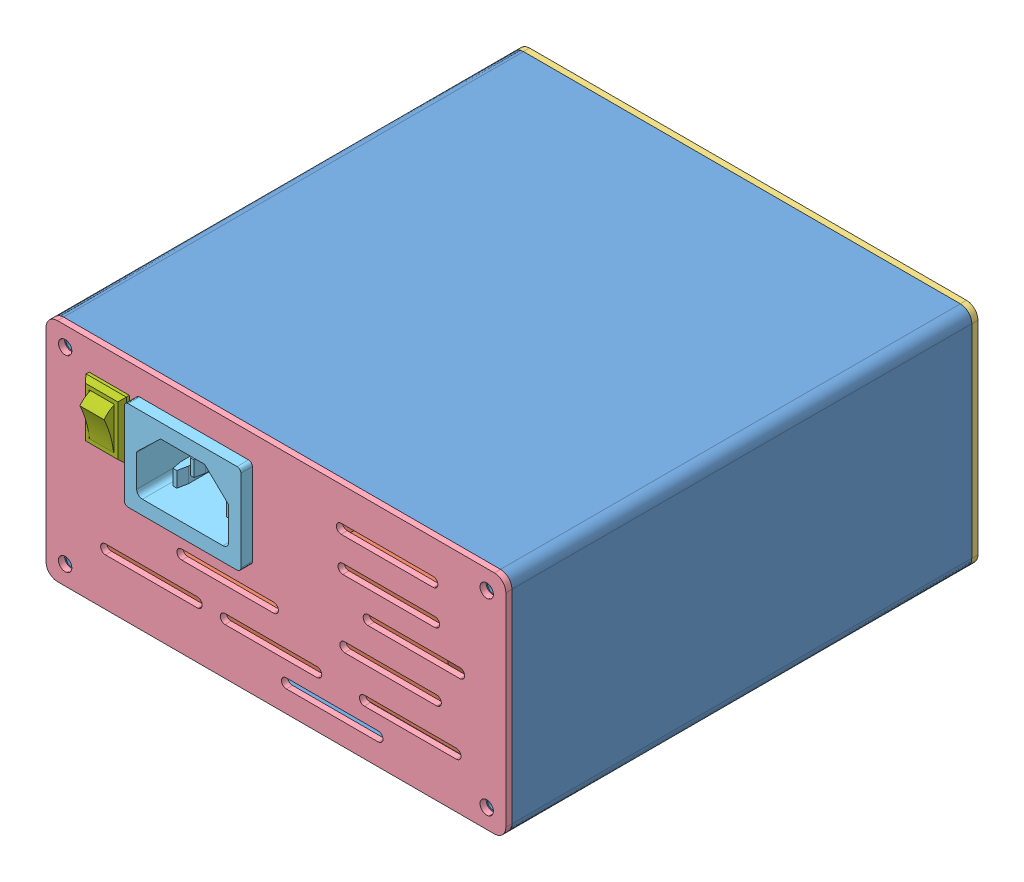
SolidWorks assembly 装配体1, configuration 默认. Lengths in mm.
Overall size (120 59 140.6).
7 component instances, 7 part files, 9 mates.
Components (placement in the parent):
- 外壳-1: 外壳 [默认] at (903.2841 10.1227 60) size (120 59 120)
- 电源板-1: 电源板 [默认] at (-16.0033 -12.8133 146.25) size (110.5 30.6 61.5)
- 外壳面板-1: 外壳面板 [默认] at (-16.0033 4.1084 60) x (-1 0 0) z (0 0 -1) size (120 59 1.6)
- 后面板-1: 后面板 [默认] at (-210.6227 -116.1807 180) size (120 59 1.6)
- 品字插座-1: 品字插座 [默认] at (-37.3533 18.9316 184.6) x (-1 0 0) z (0 0 -1) size (30.41 23.41 22)
- 焊台主控板-1: 焊台主控板 [默认] at (-19.2044 7.8959 67) x (1 0 0) z (0 -1 0) size (79 65.7 52.6)
- 船形开关-1: 船形开关 [默认] at (-59.5033 22.1816 182.4) x (0 -1 0) z (1 0 0) size (15 20 10.5)
Mates (geometry in assembly coordinates):
- 宽度1: width anti-aligned: plane of 电源板-1 through (-71.2533 -11.2133 120.5) normal (-1 0 0); plane of 电源板-1 through (39.2467 -11.2133 141.4) normal (1 0 0); plane of 外壳-1 through (-74.0033 34.1816 180) normal (1 0 0); plane of 外壳-1 through (41.9967 34.1816 180) normal (-1 0 0)
- 距离1: distance = 3 mm aligned: plane of 电源板-1 through (-66.2533 -11.2133 177) normal (0 0 1); plane of 外壳-1 through (-73.0033 -18.8184 180) normal (0 0 1)
- 轮廓中心1: profile center = 0 mm anti-aligned: plane of 外壳-1 through (-73.0033 -18.8184 60) normal (0 0 -1); plane of 外壳面板图1-1 through (-16.0033 4.1084 60) normal (0 0 1)
- 轮廓中心2: profile center = 0 mm anti-aligned: plane of 外壳-1 through (-73.0033 -18.8184 180) normal (0 0 1); plane of 后面板-1 through (-73.0033 -18.8184 180) normal (0 0 -1)
- 轮廓中心3: profile center = 0 mm anti-aligned: plane of 品字插座-1 through (-23.1462 29.6387 181.6) normal (0 0 -1); line of 后面板-1 through (-51.0033 8.6816 181.6) axis (1 0 0)
- 平行1: parallel aligned: plane of 外壳面板图1-1 through (-16.0033 -21.8184 58.4) normal (0 -1 0); plane of 焊台主控板-1 through (9.2956 -18.1041 68.6) normal (0 -1 0)
- 轮廓中心5: profile center = 1 mm aligned: plane of 焊台主控板-1 through (2.7956 -9.2041 61) normal (0 0 -1); circle of 外壳面板图1-1
- 轮廓中心6: profile center = 0 mm anti-aligned: plane of 船形开关-1 through (-59.5033 22.1816 181.6) normal (0 0 -1); line of 后面板-1 through (-64.0033 29.1816 181.6) axis (0 -1 0)
- 相切1: tangent anti-aligned: cylinder of 外壳-1 through (-71.0075 -16.8133 171) axis (0 0 1) radius 4; plane of 电源板-1 through (34.2467 -12.8133 120.5) normal (0 -1 0)
